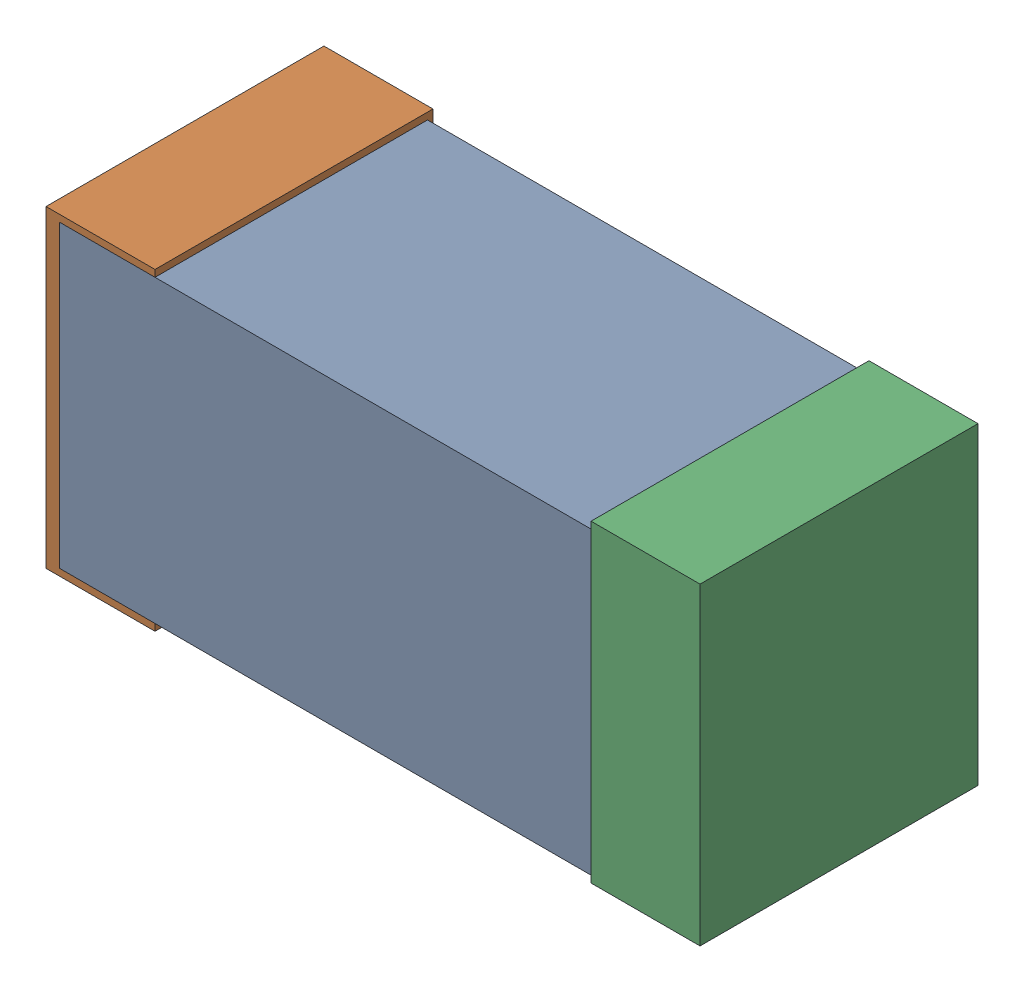
SolidWorks assembly R8, configuration Default. Lengths in mm.
Overall size (1.2 0.58 0.51).
6 component instances, 2 part files, 0 mates.
Components (placement in the parent):
- 384312640-1: 384312640 [Default] at (21.336 35.814 -1.6024) size (1.15 0.55 0.5)
  - Extruded_18-1: Extruded_18 [Default] at origin size (1.15 0.55 0.5)
- 384310976-1: 384310976 [Default] at (20.836 35.814 -1.6124) size (0.2 0.58 0.51)
  - Extruded_19-1: Extruded_19 [Default] at origin size (0.2 0.58 0.51)
- 384310976-2: 384310976 [Default] at (21.836 35.814 -1.6124) size (0.2 0.58 0.51)
  - Extruded_19-1: Extruded_19 [Default] at origin size (0.2 0.58 0.51)
